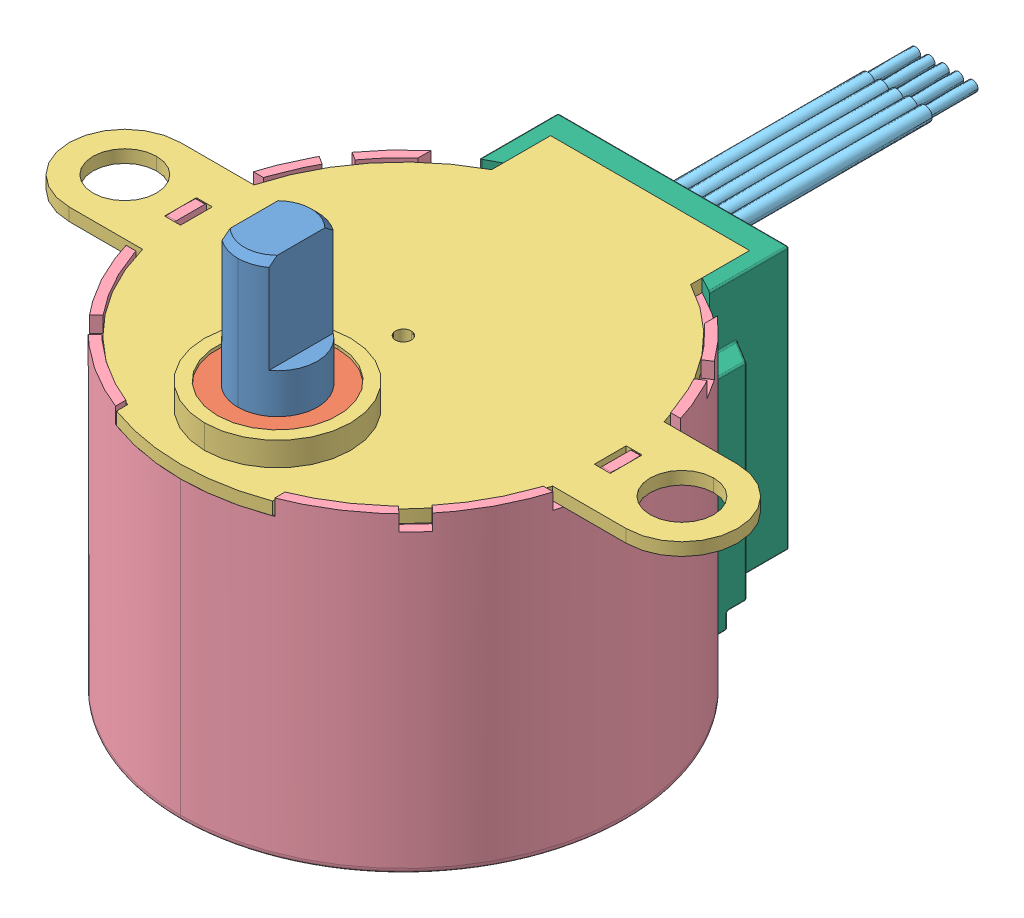
SolidWorks assembly 28BYJ-48, configuration Default. Lengths in mm.
Overall size (42 29.25 47.99).
7 component instances, 6 part files, 0 mates.
Components (placement in the parent):
- 28BYJ-48.STEP-1: 28BYJ-48.STEP [Default] at origin size (42 29.25 47.99)
  - 28BYJ-48-005.STEP-1: 28BYJ-48-005.STEP [Default] at origin size (5 18 5)
  - 28BYJ-48-003.STEP-1: 28BYJ-48-003.STEP [Default] at (0 -0.5 0) size (7.6 10 7.6)
  - 28BYJ-48-002.STEP-1: 28BYJ-48-002.STEP [Default] at (0 7.4 -7.9) size (42 2.3 29.5)
  - 28BYJ-48-001.STEP-1: 28BYJ-48-001.STEP [Default] at (0 -10.6 -7.9) size (28.73 19.65 28.03)
  - 28BYJ-48-007.STEP-1: 28BYJ-48-007.STEP [Default] at (0 5.7 -23.8765) x (-1 0 0) z (0 0 -1) size (4.5 0.9 18)
  - 28BYJ-48-006.STEP-1: 28BYJ-48-006.STEP [Default] at (0 -0.05 -24.8765) x (0 0 1) z (-1 0 0) size (6.01 17.5 17.49)
